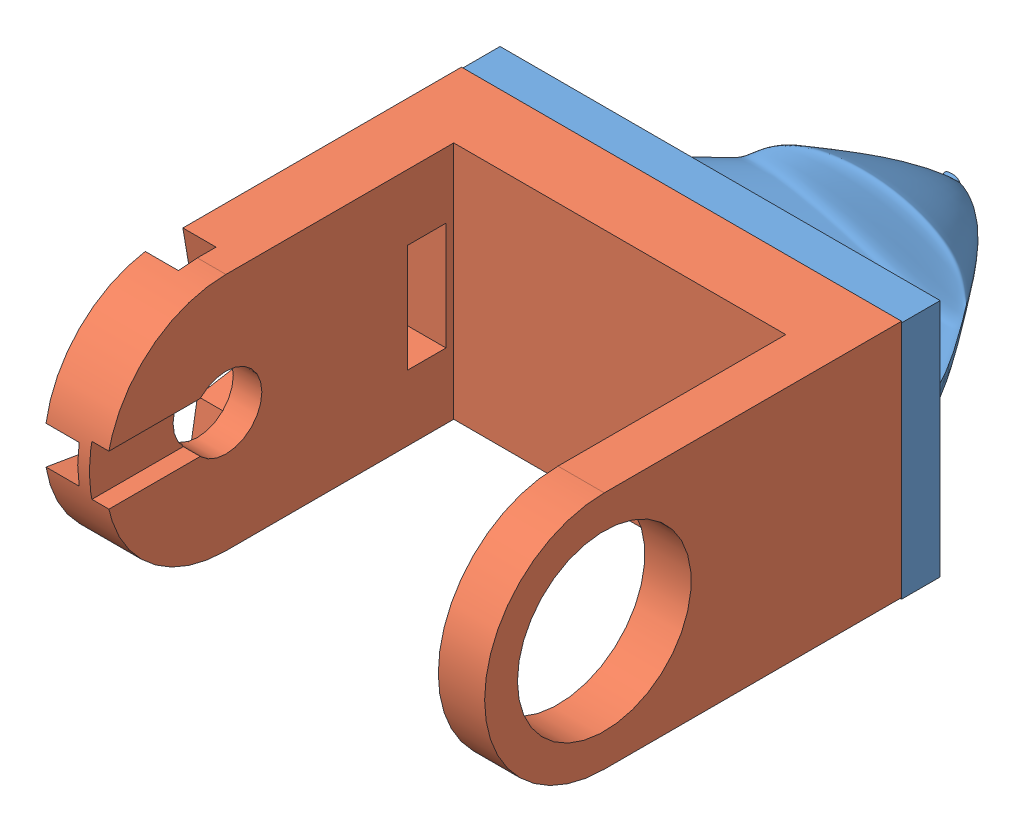
SolidWorks assembly Head, configuration Default. Lengths in mm.
Overall size (57 31.24 89.06).
2 component instances, 2 part files, 3 mates.
Components (placement in the parent):
- Head Cap-1: Head Cap [Default] at (21.9586 34.8973 52.4211) size (57 31.11 35.06)
- Nose servo mount-1: Nose servo mount [Default] at (21.9586 35.0808 66.4211) x (0 -1 0) z (0 0 -1) size (31 57 54)
Mates (geometry in assembly coordinates):
- Coincident4: coincident aligned: plane of Head Cap-1 through (50.4586 19.3973 57.4211) normal (1 0 0); plane of Nose servo mount-1 through (50.4586 19.5808 57.4211) normal (1 0 0)
- Coincident5: coincident anti-aligned: plane of Head Cap-1 through (21.9586 34.8973 57.4211) normal (0 0 1); plane of Nose servo mount-1 through (21.9586 35.0808 57.4211) normal (0 0 -1)
- Concentric1: concentric anti-aligned: circle of Head Cap-1; circle of Nose servo mount-1
